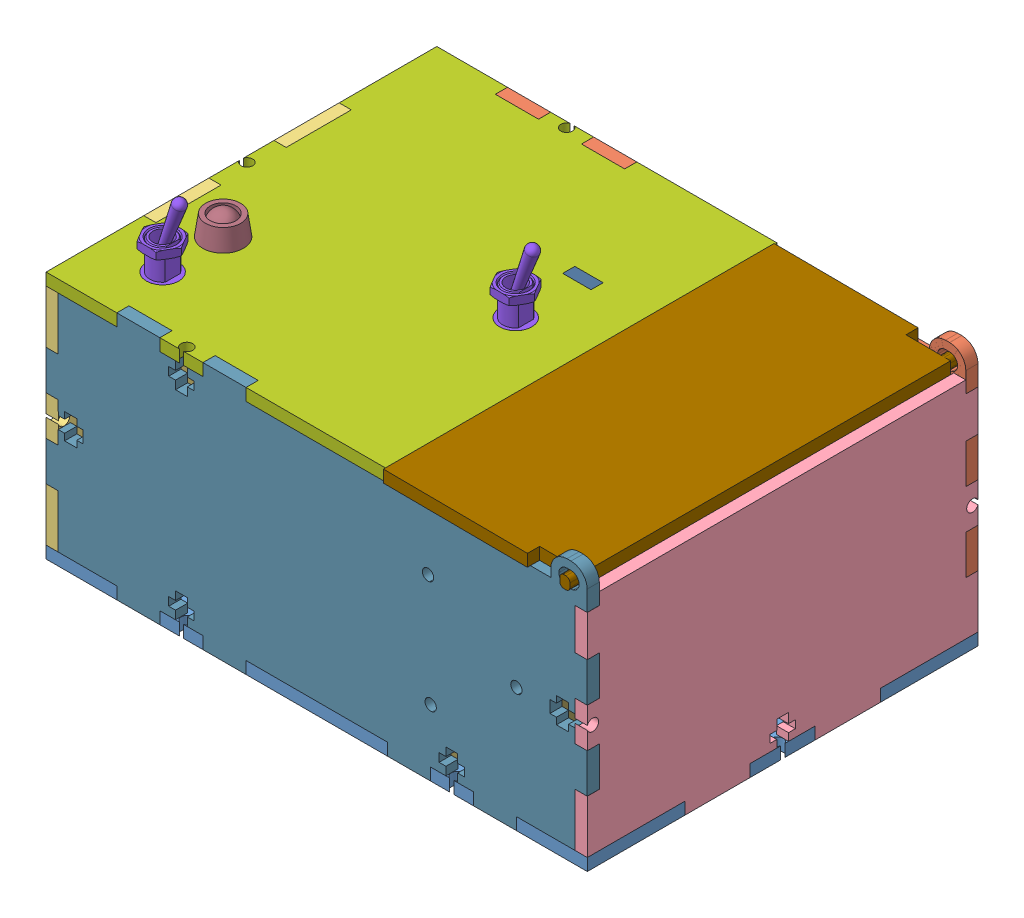
SolidWorks assembly UB3829, configuration Default. Lengths in mm.
Overall size (133.73 81 97.32).
21 component instances, 16 part files, 48 mates.
Components (placement in the parent):
- Bottom prt ub-1: Bottom prt ub [Default] at (51.6625 51.9472 109.3935) size (133.7 3 96.52)
- Right side prt2-1: Right side prt2 [Default] at (51.6362 82.6572 61.1335) size (133.7 64.42 3)
- front side prt3-1: front side prt3 [Default] at (-15.1875 82.6572 109.3935) x (0 0 -1) z (1 0 0) size (96.52 61.42 3)
- Right side prt2-2: Right side prt2 [Default] at (51.6625 82.6572 61.1335) size (133.7 64.42 3)
- Back side prt4-1: Back side prt4 [Default] at (115.5125 82.6572 109.3935) x (0 0 -1) z (0 -1 0) size (96.52 3 58.42)
- ArduinoUno-1: ArduinoUno [Default] at (16.9625 67.6472 116.1335) x (0 0 1) z (-1 0 0) size (74.8 12.1 53.3)
- Micro Servo SG92R 180-1: Micro Servo SG92R 180 [Valor predeterminado] at (52.4125 85.1172 94.1335) x (0 -1 0) z (-1 0 0) size (32 29 12)
- Top1 ub-1: Top1 ub [Default] at (18.2375 110.3672 109.3935) size (84.1 3 96.52)
- Panel Mount SPDT-1: Panel Mount SPDT [Default] at (52.5625 103.4572 109.3935) x (0 0 -1) z (1 0 0) size (8 31.74 12.7)
- Top2 prt6-2: Top2 prt6 [Default] at (83.5882 110.5742 110.1948) x (0.999979 -0.006485 0) z (0 0 1) size (46.6 3 96.52)
- Part3-1: Part3 [Default] at (52.4125 82.6572 91.1335) size (15 61.42 3)
- arm-3: arm [Default] at (60.2627 108.7708 114.7967) x (0.972962 0.230967 0) z (-0.230967 0.972962 0) size (51.51 30 37.14)
- Micro Servo Horn Single Arm-1: Micro Servo Horn Single Arm [Default] at (52.4125 90.3672 107.4129) x (-0.381065 0.924548 0) z (0.924548 0.381065 0) size (19.74 4.23 7.24) (hidden)
- Panel Mount SPDT-2: Panel Mount SPDT [Default] at (-0.8375 103.4572 143.2235) x (0 0 -1) z (1 0 0) size (8 31.74 12.7)
- 9V Battery Holder-1: 9V Battery Holder [Default] at (90.1936 82.3081 153.6535) x (-0.023896 0.999714 0) z (0 0 -1) size (53.5 30 19.31)
- Panel Mount LED-1: Panel Mount LED [Default] at (-0.8905 103.3672 128.2235) size (11.13 16 10.04)
- left side-1: left side [Default] at (51.6353 82.6572 154.6535) size (133.7 64.42 3)
- .25x.5 Aluminum Hex Male Female Standoff-1: .25x.5 Aluminum Hex Male Female Standoff [Default] at (41.1125 61.2972 98.7335) x (-0.837169 0 -0.546944) z (0 1 0) size (6.35 8.06 17.45)
- .25x.5 Aluminum Hex Male Female Standoff-3: .25x.5 Aluminum Hex Male Female Standoff [Default] at (25.8125 61.2972 149.5335) x (-0.837169 0 -0.546944) z (0 1 0) size (6.35 8.06 17.45)
- .25x.5 Aluminum Hex Male Female Standoff-4: .25x.5 Aluminum Hex Male Female Standoff [Default] at (-7.1875 61.2972 97.1335) x (-0.837169 0 -0.546944) z (0 1 0) size (6.35 8.06 17.45)
- .25x.5 Aluminum Hex Male Female Standoff-5: .25x.5 Aluminum Hex Male Female Standoff [Default] at (-2.0875 61.2972 149.5335) x (-0.837169 0 -0.546944) z (0 1 0) size (6.35 8.06 17.45)
Mates (geometry in assembly coordinates):
- Coincident2: coincident: plane of Bottom prt ub-1 through (12.9167 54.9472 61.1335) normal (-1 0 0); plane of Right side prt2-1 through (12.9167 54.9472 64.1335) normal (1 0 0)
- Coincident3: coincident: line of Bottom prt ub-1 through (2.275 51.9472 64.1335) axis (1 0 0); line of Right side prt2-1 through (2.2759 51.9472 64.1335) axis (1 0 0)
- Coincident5: coincident: plane of Bottom prt ub-1 through (51.6625 54.9472 109.3935) normal (0 1 0); plane of Right side prt2-1 through (-12.2138 54.9472 64.1335) normal (0 -1 0)
- Coincident6: coincident: line of Bottom prt ub-1 through (-12.1875 51.9472 117.4369) axis (0 0 1); line of front side prt3-1 through (-12.1875 51.9472 133.5235) axis (0 0 -1)
- Coincident7: coincident: plane of Bottom prt ub-1 through (-12.1875 54.9472 85.2635) normal (0 0 1); plane of front side prt3-1 through (-15.1875 51.9472 85.2635) normal (0 0 -1)
- Coincident8: coincident: plane of Bottom prt ub-1 through (51.6625 54.9472 109.3935) normal (0 1 0); plane of front side prt3-1 through (-15.1875 54.9472 109.3935) normal (0 -1 0)
- Coincident13: coincident: plane of Bottom prt ub-1 through (51.6625 54.9472 109.3935) normal (0 1 0); plane of Back side prt4-1 through (115.5125 54.9472 109.3935) normal (0 -1 0)
- Coincident14: coincident: plane of Bottom prt ub-1 through (115.5125 54.9472 85.2635) normal (0 0 1); plane of Back side prt4-1 through (118.5125 51.9472 85.2635) normal (0 0 -1)
- Coincident15: coincident: plane of Bottom prt ub-1 through (115.5125 51.9472 109.3935) normal (1 0 0); plane of Back side prt4-1 through (115.5125 82.6572 109.3935) normal (-1 0 0)
- Concentric1: concentric: cylinder of Bottom prt ub-1 through (-2.0875 51.9472 149.5335) axis (0 1 0) radius 1.6; cylinder of ArduinoUno-1 through (-2.0875 69.2472 149.5335) axis (0 -1 0) radius 1.6
- Concentric2: concentric: cylinder of Bottom prt ub-1 through (25.8125 51.9472 149.5335) axis (0 1 0) radius 1.6; cylinder of ArduinoUno-1 through (25.8125 69.2472 149.5335) axis (0 -1 0) radius 1.6
- Coincident25: coincident: plane of front side prt3-1 through (-12.1875 82.6572 109.3935) normal (1 0 0); plane of Top1 ub-1 through (-12.1875 110.3672 109.3935) normal (-1 0 0)
- Coincident26: coincident: plane of front side prt3-1 through (-15.1875 113.3672 85.2635) normal (0 0 -1); plane of Top1 ub-1 through (-12.1875 113.3672 85.2635) normal (0 0 1)
- Coincident27: coincident: line of front side prt3-1 through (-12.1875 113.3672 133.5235) axis (0 0 -1); line of Top1 ub-1 through (-12.1875 113.3672 117.4369) axis (0 0 1)
- Coincident32: coincident: line of Back side prt4-1 through (115.5125 110.3672 64.1335) axis (0 0 1); line of Top2 prt6-2 through (115.5125 110.3672 155.4548) axis (0 0 -1)
- Coincident33: coincident: plane of Bottom prt ub-1 through (51.6625 54.9472 109.3935) normal (0 1 0); plane of Part3-1 through (59.9125 54.9472 91.1335) normal (0 -1 0)
- Coincident36: coincident: plane of Micro Servo SG92R 180-1 through (52.4125 71.4922 94.1335) normal (0 0 -1); plane of Part3-1 through (52.4125 82.6572 94.1335) normal (0 0 1)
- Coincident37: coincident: plane of Bottom prt ub-1 through (48.9125 51.9472 91.1335) normal (0 0 1); plane of Part3-1 through (52.4125 82.6572 91.1335) normal (0 0 -1)
- Coincident38: coincident: plane of Bottom prt ub-1 through (48.9125 51.9472 91.1335) normal (1 0 0); plane of Part3-1 through (48.9125 51.9472 91.1335) normal (-1 0 0)
- Coincident39: coincident: plane of arm-3 through (52.4745 90.5546 109.0258) normal (0 0 -1); plane of Micro Servo Horn Single Arm-1 through (52.4125 90.3672 109.0258) normal (0 0 1)
- Concentric3: concentric: cylinder of arm-3 through (57.8183 77.2516 109.0258) axis (0 0 -1) radius 1.9304; cylinder of Micro Servo Horn Single Arm-1 through (57.8183 77.2516 109.0258) axis (0 0 -1) radius 1.9304
- Concentric4: concentric: cylinder of Micro Servo SG92R 180-1 through (52.4125 90.3672 107.1335) axis (0 0 -1) radius 2.25; cylinder of Micro Servo Horn Single Arm-1 through (52.4125 90.3672 107.1335) axis (0 0 -1) radius 2.286
- Coincident47: coincident: plane of Micro Servo SG92R 180-1 through (52.4125 90.3672 107.1335) normal (0 0 1); plane of Micro Servo Horn Single Arm-1 through (52.4125 90.3672 107.1335) normal (0 0 -1)
- Parallel4: parallel: plane of arm-3 through (55.9734 76.6835 109.0258) normal (0.890456 0.45507 0); plane of Micro Servo Horn Single Arm-1 through (56.0994 76.3731 109.0258) normal (-0.890456 -0.45507 0)
- Coincident52: coincident: circle of Top1 ub-1; circle of Panel Mount SPDT-2
- Coincident53: coincident: circle of Top1 ub-1; circle of Panel Mount SPDT-1
- Coincident54: coincident: circle of Top1 ub-1; circle of Panel Mount LED-1
- Coincident55: coincident: plane of Micro Servo SG92R 180-1 through (58.4125 96.3672 78.1335) normal (0 1 0); plane of Part3-1 through (46.4125 96.3672 91.1335) normal (0 -1 0)
- Coincident56: coincident: plane of Micro Servo SG92R 180-1 through (58.4125 96.3672 78.1335) normal (1 0 0); plane of Part3-1 through (58.4125 96.3672 91.1335) normal (-1 0 0)
- Coincident64: coincident: line of Bottom prt ub-1 through (34.2 54.9472 61.1335) axis (1 0 0); line of Right side prt2-2 through (34.2272 54.9472 61.1335) axis (1 0 0)
- Coincident65: coincident: line of front side prt3-1 through (-15.1875 87.5261 64.1335) axis (0 1 0); line of Right side prt2-2 through (-15.1875 87.5261 64.1335) axis (0 1 0)
- Coincident70: coincident: line of Bottom prt ub-1 through (34.2 54.9472 157.6535) axis (1 0 0); line of left side-1 through (34.2 54.9472 157.6535) axis (1 0 0)
- Coincident71: coincident: plane of Bottom prt ub-1 through (34.2 54.9472 154.6535) normal (-1 0 0); plane of left side-1 through (34.2 51.9472 157.6535) normal (1 0 0)
- Parallel9: parallel: line of front side prt3-1 through (-15.1875 87.5261 154.6535) axis (0 1 0); line of left side-1 through (-15.2147 97.2622 154.6535) axis (0 -1 0)
- Coincident74: coincident: plane of 9V Battery Holder-1 through (79.1681 95.7985 154.6535) normal (0 0 1); plane of left side-1 through (51.6353 82.6572 154.6535) normal (0 0 -1)
- Parallel11: parallel: plane of 9V Battery Holder-1 through (90.1936 82.3081 153.6535) normal (0 0 1); plane of left side-1 through (51.6353 82.6572 154.6535) normal (0 0 -1)
- Coincident78: coincident: circle of 9V Battery Holder-1; circle of left side-1
- Coincident79: coincident: circle of 9V Battery Holder-1; circle of left side-1
- Concentric5: concentric: cylinder of Bottom prt ub-1 through (-2.0875 51.9472 149.5335) axis (0 1 0) radius 1.6; cylinder of .25x.5 Aluminum Hex Male Female Standoff-5 through (-2.0875 50.1972 149.5335) axis (0 1 0) radius 1.05
- Coincident80: coincident: plane of Bottom prt ub-1 through (51.6625 54.9472 109.3935) normal (0 1 0); plane of .25x.5 Aluminum Hex Male Female Standoff-5 through (-2.0875 54.9472 149.5335) normal (0 -1 0)
- Coincident82: coincident: plane of ArduinoUno-1 through (43.6125 67.6472 149.1335) normal (0 -1 0); plane of .25x.5 Aluminum Hex Male Female Standoff-5 through (-2.0875 67.6472 149.5335) normal (0 1 0)
- Concentric6: concentric: cylinder of Bottom prt ub-1 through (-7.1875 51.9472 97.1335) axis (0 1 0) radius 1.6; cylinder of .25x.5 Aluminum Hex Male Female Standoff-4 through (-7.1875 50.1972 97.1335) axis (0 1 0) radius 1.05
- Coincident83: coincident: plane of Bottom prt ub-1 through (51.6625 54.9472 109.3935) normal (0 1 0); plane of .25x.5 Aluminum Hex Male Female Standoff-4 through (-7.1875 54.9472 97.1335) normal (0 -1 0)
- Coincident84: coincident: plane of ArduinoUno-1 through (43.6125 67.6472 149.1335) normal (0 -1 0); plane of .25x.5 Aluminum Hex Male Female Standoff-4 through (-7.1875 67.6472 97.1335) normal (0 1 0)
- Concentric7: concentric: cylinder of Bottom prt ub-1 through (25.8125 51.9472 149.5335) axis (0 1 0) radius 1.6; cylinder of .25x.5 Aluminum Hex Male Female Standoff-3 through (25.8125 50.1972 149.5335) axis (0 1 0) radius 1.05
- Coincident85: coincident: plane of Bottom prt ub-1 through (51.6625 54.9472 109.3935) normal (0 1 0); plane of .25x.5 Aluminum Hex Male Female Standoff-3 through (25.8125 54.9472 149.5335) normal (0 -1 0)
- Concentric8: concentric: cylinder of Bottom prt ub-1 through (41.1125 51.9472 98.7335) axis (0 1 0) radius 1.6; cylinder of .25x.5 Aluminum Hex Male Female Standoff-1 through (41.1125 50.1972 98.7335) axis (0 1 0) radius 1.05
- Coincident86: coincident: plane of Bottom prt ub-1 through (51.6625 54.9472 109.3935) normal (0 1 0); plane of .25x.5 Aluminum Hex Male Female Standoff-1 through (41.1125 54.9472 98.7335) normal (0 -1 0)
